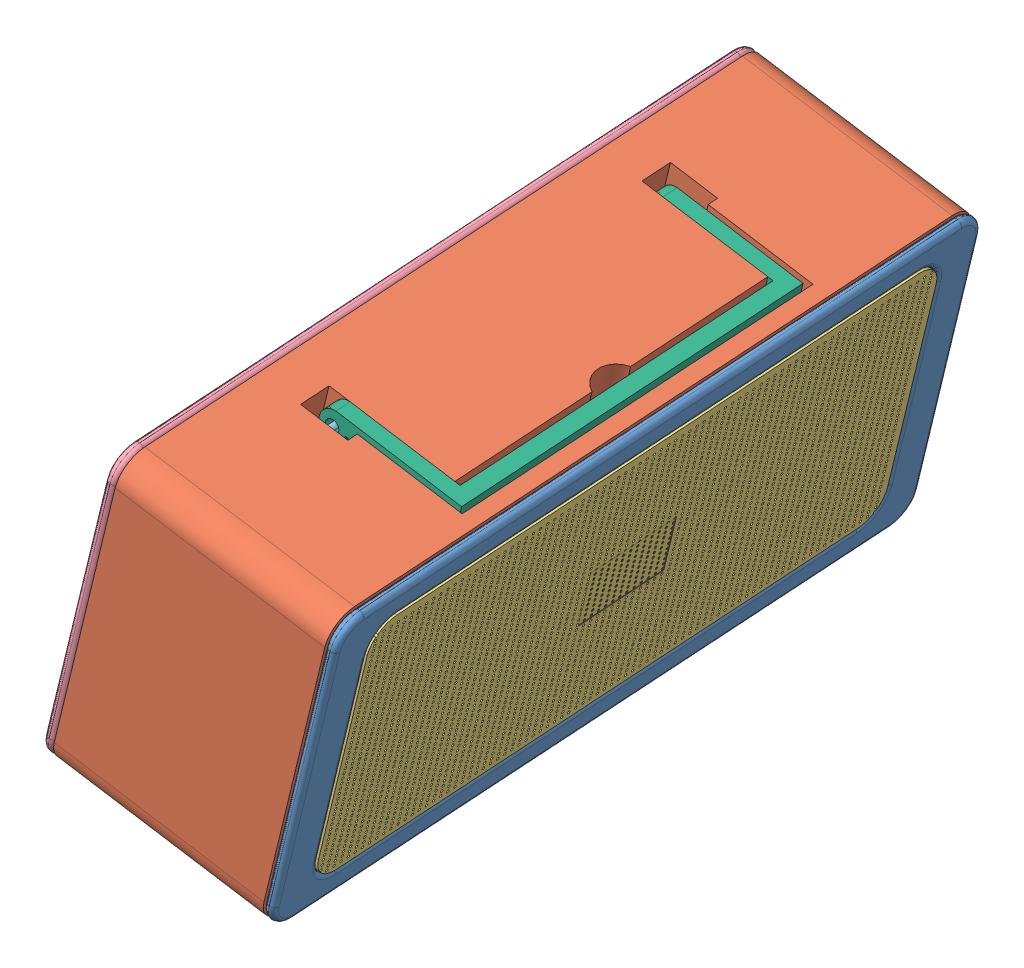
SolidWorks assembly speaker, configuration Default. Lengths in mm.
Overall size (64.85 68.49 139.32).
7 component instances, 6 part files, 18 mates.
Components (placement in the parent):
- blue_part-1: blue_part [Default] at (20.4815 60.3841 98.431) x (0.972346 -0.225381 -0.061204) z (0.063015 0.000842 0.998012) size (4.5 60 136)
- Body-1: Body [Default] at (20.4815 60.3841 98.431) x (0.972346 -0.225381 -0.061204) z (0.063015 0.000842 0.998012) size (40 60 136)
- weldment-2: weldment [Default<As Machined>] at (22.4262 59.9333 98.3086) x (-0.972346 0.225381 0.061204) z (-0.063015 -0.000842 -0.998012) size (2 50 120)
- back-1: back [Default] at (-20.357 69.8501 101.0016) x (-0.063015 -0.000842 -0.998012) z (0.972346 -0.225381 -0.061204) size (136 60 2)
- rod-1: rod [Default] at (-4.6588 91.2456 59.4117) x (0.998013 -0.000027 -0.063015) z (0.063015 0.000842 0.998012) size (2.5 2.5 9)
- rod-2: rod [Default] at (-0.1217 91.3062 131.2686) x (0.998013 -0.000027 -0.063015) z (0.063015 0.000842 0.998012) size (2.5 2.5 9)
- Hanger-3: Hanger [Default] at (19.7376 88.2692 98.4545) x (0.063015 0.000842 0.998012) z (0.224881 0.97427 -0.015021) size (72 26.5 13)
Mates (geometry in assembly coordinates):
- Coincident5: coincident anti-aligned: plane of blue_part-1 through (10.8896 35.9743 35.9318) normal (-0.972346 0.225381 0.061204); plane of Body-1 through (30.0735 84.7939 160.9303) normal (0.972346 -0.225381 -0.061204)
- Coincident6: coincident: line of blue_part-1 through (32.1702 89.4399 160.794) axis (-0.063015 -0.000842 -0.998012); plane of Body-1 through (-7.696 98.6805 163.3033) normal (0.224881 0.97427 -0.015021)
- Coincident7: coincident: line of blue_part-1 through (20.1169 35.8592 166.6102) axis (0.224881 0.97427 -0.015021); plane of Body-1 through (-19.7494 45.0998 169.1195) normal (0.063015 0.000842 0.998012)
- Coincident8: coincident anti-aligned: plane of blue_part-1 through (21.7095 40.4984 158.4898) normal (-0.063015 -0.000842 -0.998012); plane of weldment-2 through (19.7648 40.9492 158.6122) normal (0.063015 0.000842 0.998012)
- Coincident9: coincident aligned: plane of blue_part-1 through (12.8343 35.5235 35.8094) normal (0.972346 -0.225381 -0.061204); plane of weldment-2 through (23.4581 79.3724 43.1175) normal (0.972346 -0.225381 -0.061204)
- Coincident10: coincident anti-aligned: plane of blue_part-1 through (31.5141 84.3364 152.8238) normal (-0.224881 -0.97427 0.015021); plane of weldment-2 through (22.6378 84.6945 43.1648) normal (0.224881 0.97427 -0.015021)
- Coincident14: coincident anti-aligned: plane of Body-1 through (-8.8204 93.8091 163.3784) normal (-0.972346 0.225381 0.061204); plane of back-1 through (-20.0644 45.0956 164.1295) normal (0.972346 -0.225381 -0.061204)
- Coincident15: coincident: plane of Body-1 through (-19.7494 45.0998 169.1195) normal (0.063015 0.000842 0.998012); line of back-1 through (-20.7217 45.3252 169.1808) axis (0.224881 0.97427 -0.015021)
- Coincident16: coincident: plane of Body-1 through (-7.696 98.6805 163.3033) normal (0.224881 0.97427 -0.015021); line of back-1 through (-8.6683 98.9059 163.3645) axis (-0.063015 -0.000842 -0.998012)
- Coincident21: coincident anti-aligned: plane of Body-1 through (-4.6588 91.2456 59.4117) normal (0.063015 0.000842 0.998012); plane of rod-1 through (-4.6588 91.2456 59.4117) normal (-0.063015 -0.000842 -0.998012)
- Coincident22: coincident anti-aligned: plane of Body-1 through (-4.0916 91.2532 68.3938) normal (-0.063015 -0.000842 -0.998012); plane of rod-1 through (-4.0916 91.2532 68.3938) normal (0.063015 0.000842 0.998012)
- Concentric2: concentric aligned: cylinder of Body-1 through (-4.0916 91.2532 68.3938) axis (-0.063015 -0.000842 -0.998012) radius 1.25; cylinder of rod-1 through (-4.0916 91.2532 68.3938) axis (-0.063015 -0.000842 -0.998012) radius 1.25
- Coincident23: coincident anti-aligned: plane of Body-1 through (-0.1217 91.3062 131.2686) normal (0.063015 0.000842 0.998012); plane of rod-2 through (-0.1217 91.3062 131.2686) normal (-0.063015 -0.000842 -0.998012)
- Coincident24: coincident anti-aligned: plane of Body-1 through (0.4454 91.3138 140.2507) normal (-0.063015 -0.000842 -0.998012); plane of rod-2 through (0.4454 91.3138 140.2507) normal (0.063015 0.000842 0.998012)
- Concentric3: concentric anti-aligned: cylinder of Body-1 through (-0.1217 91.3062 131.2686) axis (0.063015 0.000842 0.998012) radius 1.25; cylinder of rod-2 through (0.4454 91.3138 140.2507) axis (-0.063015 -0.000842 -0.998012) radius 1.25
- Coincident39: coincident aligned: plane of Body-1 through (-7.696 98.6805 163.3033) normal (0.224881 0.97427 -0.015021); plane of Hanger-3 through (20.4123 91.192 98.4094) normal (0.224881 0.97427 -0.015021)
- Distance2: distance = 1 mm anti-aligned: plane of Hanger-3 through (22.6808 91.2223 134.3379) normal (0.063015 0.000842 0.998012); plane of Body-1 through (24.3844 80.5789 135.2413) normal (-0.063015 -0.000842 -0.998012)
- Distance4: distance = 1 mm anti-aligned: plane of Hanger-3 through (20.4123 91.192 98.4094) normal (-0.972346 0.225381 0.061204); plane of Body-1 through (15.1116 81.6469 65.6864) normal (0.972346 -0.225381 -0.061204)
